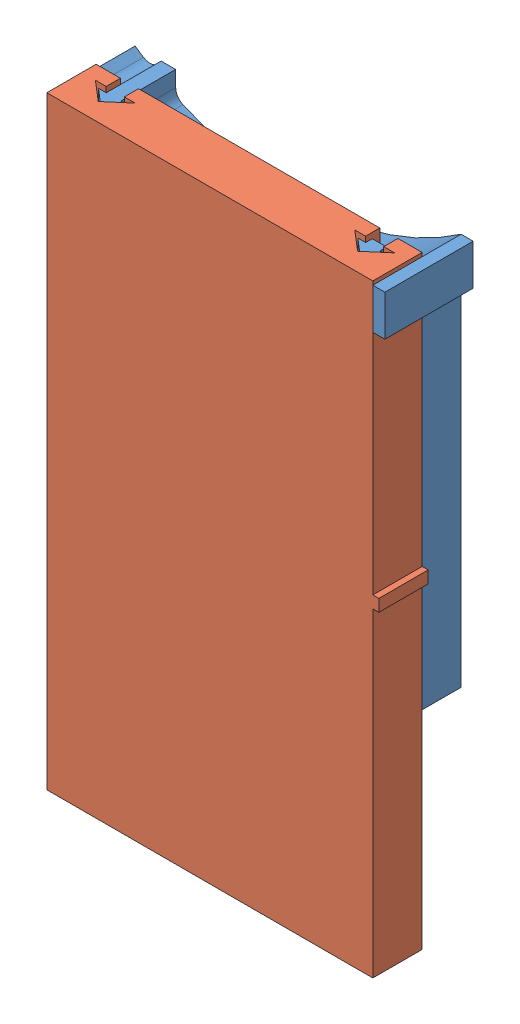
SolidWorks assembly Ensamblaje1, configuration Predeterminado. Lengths in mm.
Overall size (59.69 100 14.63).
4 component instances, 3 part files, 8 mates.
Components (placement in the parent):
- partealta-1: partealta [Predeterminado] at (-8.1885 -58.4628 -4.0939) size (56 65 14.63)
- partebaja-1: partebaja [Predeterminado] at (-7.0455 -57.8497 12.6904) size (55 100 8.17)
- portamoneda-3: portamoneda [Default] at (-7.0455 10.2338 2.2596) x (0.464191 -0.885735 0) z (-0.885735 -0.464191 0) size (37.5 3.5 43.57)
- portamoneda-4: portamoneda [Default] at (-6.8194 9.909 2.2596) x (-0.456493 0.889727 0) z (-0.889727 -0.456493 0) size (37.5 3.5 43.57)
Mates (geometry in assembly coordinates):
- Coincident16: coincident: plane of assembly; plane of assembly; plane of partealta-1 through (19.9545 41.5372 -4.0939) normal (1 0 0); plane of partebaja-1 through (19.9545 42.1503 12.6904) normal (1 0 0)
- Coincident17: coincident: plane of assembly; plane of assembly; plane of partealta-1 through (-34.0455 41.5372 2.3596) normal (0 0 1); plane of partebaja-1 through (-7.0455 42.1503 2.3596) normal (0 0 -1)
- Concentric7: concentric: circle of assembly; circle of assembly; circle of partebaja-1; circle of portamoneda-3
- Tangent3: tangent: cylinder of assembly; cylinder of assembly; cylinder of partealta-1 through (-7.0455 9.7026 -55.6176) axis (0 0 1) radius 19.0562; cylinder of portamoneda-4 through (-6.8194 9.909 0.4596) axis (0 0 1) radius 18.75
- Coincident28: coincident: plane of assembly; plane of assembly; plane of portamoneda-3 through (-7.0455 10.2338 2.2596) normal (0 0 -1); plane of portamoneda-4 through (-6.8194 9.909 2.2596) normal (0 0 1)
- Coincident32: coincident: plane of assembly; plane of assembly; plane of partebaja-1 through (-7.0455 10.2338 5.7596) normal (0 0 -1); plane of portamoneda-3 through (-7.0455 10.2338 5.7596) normal (0 0 1)
- Concentric9: concentric: cylinder of assembly; cylinder of assembly; cylinder of portamoneda-3 through (-23.1529 -4.9996 3.9596) axis (0 0 -1) radius 1; cylinder of portamoneda-4 through (-23.1529 -4.9996 0.5596) axis (0 0 1) radius 1
- Coincident33: coincident: point of assembly; cylinder of assembly; moEndPointRef_w of partebaja-1; cylinder of portamoneda-3 through (-24.0518 -4.3238 3.9596) axis (0 0 -1) radius 3
